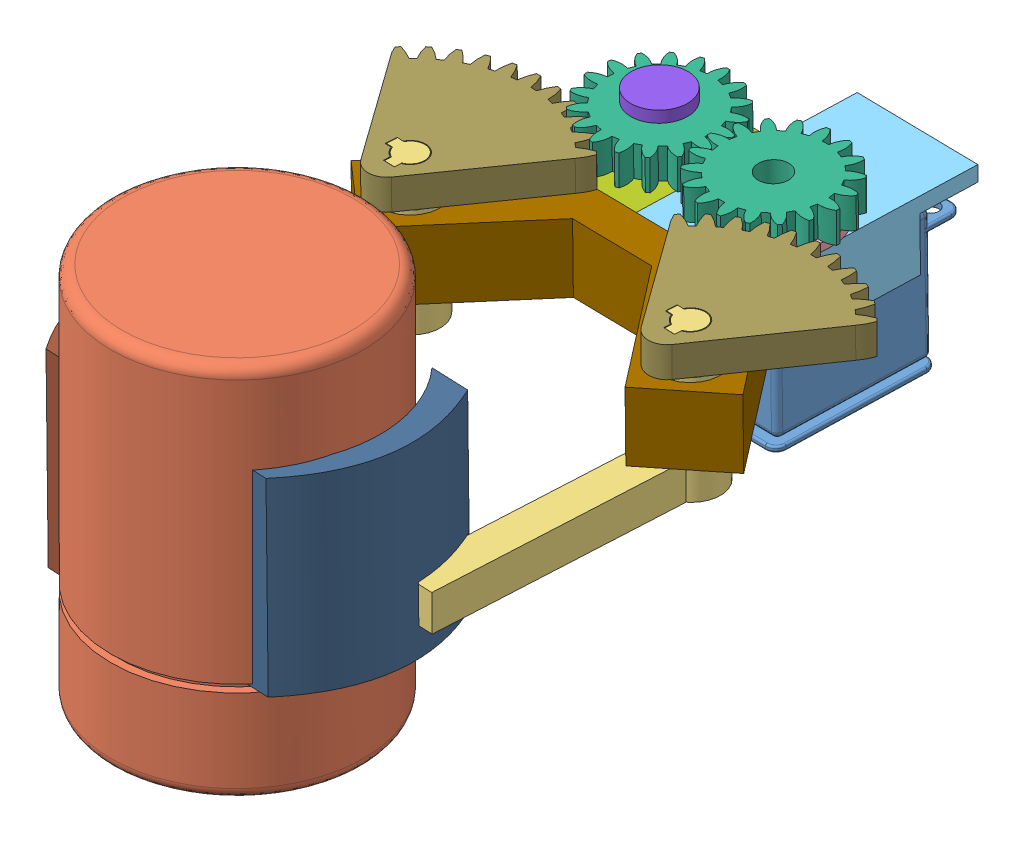
SolidWorks assembly grabber, configuration Default. Lengths in mm.
Overall size (131.25 100 194.6).
15 component instances, 12 part files, 33 mates.
Components (placement in the parent):
- servo-1: servo [Default] at (87.0204 35.4416 14.5462) x (0.029864 0.0013 -0.999553) z (0.999469 0.013011 0.029879) size (56.4 46.15 25.5)
- Can-1: Can [Default] at (74.9527 -0.4819 146.8491) size (67 100 67)
- arm_things-1: arm_things [Default] at (116.9975 33.3778 104.811) x (-0.998549 -0.013024 -0.052251) z (0.052261 -0.000408 -0.998633) size (15 36.5 77.5)
- arm_things-2: arm_things [Default] at (40.0716 32.3764 102.5067) x (-0.998256 -0.013026 -0.057587) z (0.057596 -0.000338 -0.99834) size (15 36.5 77.5)
- smol_white_disc_thing-1: smol_white_disc_thing [Default] at (96.3877 58.9257 25.6615) x (0.99304 0.013061 -0.117048) z (0.11705 0.000622 0.993126) size (30 3.9 30)
- servo_mount-1: servo_mount [Default] at (77.9364 42.1729 14.2653) x (0.999469 0.013011 0.029879) z (-0.02989 0.000699 0.999553) size (35.55 36.2 57.02)
- spur gear_iso-3: spur gear_iso [ISO - Spur gear 1.75M 18T 20PA 8mmFW ---S18A75H50L8.0N] at (96.3369 62.8253 25.665) x (-0.013044 0.999915 0.000911) z (-0.778096 -0.010723 0.628054) size (8 34.62 35)
- spur gear_iso-4: spur gear_iso [ISO - Spur gear 1.75M 18T 20PA 8mmFW ---S18A75H50L8.0N] at (65.1467 62.1199 24.7538) x (-0.012985 0.999915 -0.001088) z (0.609442 0.008776 0.792782) size (8 34.62 35)
- servo_primary_gear_mount_thingy-1: servo_primary_gear_mount_thingy [Default] at (67.6101 55.435 42.47) x (-0.999469 -0.013011 -0.029879) z (0.02989 -0.000699 -0.999553) size (27.5 27.5 35)
- pin_dongley-1: pin_dongley [Default] at (65.0889 64.699 26.8033) x (0.999845 0.012997 0.011858) z (-0.011871 0.000933 0.999929) size (15 17 15)
- big_gear_sticky_thing-1: big_gear_sticky_thing [Default] at (82.3629 42.3781 58.1562) x (0.999469 0.013011 0.029879) z (-0.02989 0.000699 0.999553) size (107.35 18 41.03)
- left_grabby_hand-1: left_grabby_hand [Default] at (76.5862 25.3944 143.4432) x (-0.998549 -0.013024 -0.052251) z (0.052261 -0.000408 -0.998633) size (16.77 50 47.38)
- right_grabby_hand-1: right_grabby_hand [Default] at (76.1966 25.3914 145.3489) x (-0.998256 -0.013026 -0.057587) z (0.057596 -0.000338 -0.99834) size (16.77 50 47.38)
- big_boi_gear_left-1: big_boi_gear_left [Default] at (123.0814 63.1664 59.9132) x (-0.012985 0.999915 -0.001088) z (0.998549 0.013024 0.052251) size (8 45.26 52.07)
- big_boi_gear_left-2: big_boi_gear_left [Default] at (46.3951 62.1681 57.6441) x (-0.012985 0.999915 -0.001088) z (0.998256 0.013026 0.057587) size (8 45.26 52.07)
Mates (geometry in assembly coordinates):
- Coincident8: coincident anti-aligned: line of servo-1 through (96.3482 61.9554 25.6642) axis (0.013044 -0.999915 -0.000911); line of smol_white_disc_thing-1 through (96.3877 58.9257 25.6615) axis (-0.013044 0.999915 0.000911)
- Coincident10: coincident anti-aligned: plane of servo-1 through (96.3482 61.9554 25.6642) normal (-0.013044 0.999915 0.000911); plane of smol_white_disc_thing-1 through (96.3482 61.9554 25.6642) normal (0.013044 -0.999915 -0.000911)
- Coincident11: coincident aligned: line of servo-1 through (84.3492 28.1285 -10.054) axis (-0.999469 -0.013011 -0.029879); line of servo_mount-1 through (82.85 28.109 -10.0989) axis (-0.999469 -0.013011 -0.029879)
- Distance1: distance = 0.1 mm: line of servo_mount-1 through (81.3847 28.1433 38.8992) axis (-0.999469 -0.013011 -0.029879); line of servo-1 through (82.8858 28.0648 38.9241) axis (-0.999469 -0.013011 -0.029879)
- Coincident12: coincident anti-aligned: plane of servo-1 through (82.0231 35.3765 14.3968) normal (-0.999469 -0.013011 -0.029879); plane of servo_mount-1 through (81.9343 42.2249 14.3848) normal (0.999469 0.013011 0.029879)
- Coincident15: coincident anti-aligned: line of smol_white_disc_thing-1 through (96.3629 60.8255 25.6632) axis (-0.013044 0.999915 0.000911); line of spur gear_iso-3 through (96.2325 70.8246 25.6723) axis (0.013044 -0.999915 -0.000911)
- Coincident16: coincident anti-aligned: plane of smol_white_disc_thing-1 through (96.3369 62.8253 25.665) normal (-0.013044 0.999915 0.000911); plane of spur gear_iso-3 through (96.3369 62.8253 25.665) normal (0.013044 -0.999915 -0.000911)
- Coincident17: coincident aligned: line of servo_mount-1 through (78.5536 60.2514 -14.2516) axis (-0.02989 0.000699 0.999553); line of servo_primary_gear_mount_thingy-1 through (77.8954 60.2668 7.7585) axis (-0.02989 0.000699 0.999553)
- Coincident18: coincident aligned: line of servo_mount-1 through (76.8492 60.2913 42.7429) axis (0.012985 -0.999915 0.001088); line of servo_primary_gear_mount_thingy-1 through (76.8492 60.2913 42.7429) axis (0.012985 -0.999915 0.001088)
- Coincident23: coincident anti-aligned: plane of servo_primary_gear_mount_thingy-1 through (65.2116 57.1204 24.7592) normal (-0.012985 0.999915 -0.001088); plane of pin_dongley-1 through (65.1647 57.124 28.7089) normal (0.012985 -0.999915 0.001088)
- Coincident25: coincident aligned: line of servo_primary_gear_mount_thingy-1 through (65.2116 57.1204 24.7592) axis (-0.012985 0.999915 -0.001088); line of pin_dongley-1 through (65.2116 57.1204 24.7592) axis (-0.012985 0.999915 -0.001088)
- Coincident29: coincident anti-aligned: line of spur gear_iso-4 through (65.0428 70.1192 24.7451) axis (0.012985 -0.999915 0.001088); line of pin_dongley-1 through (65.2116 57.1204 24.7592) axis (-0.012985 0.999915 -0.001088)
- Coincident30: coincident anti-aligned: plane of spur gear_iso-4 through (65.1467 62.1199 24.7538) normal (0.012985 -0.999915 0.001088); plane of servo_primary_gear_mount_thingy-1 through (65.1467 62.1199 24.7538) normal (-0.012985 0.999915 -0.001088)
- GearMate1: gear = 18 : 18 mm: line of spur gear_iso-3 through (96.2325 70.8246 25.6723) axis (0.013044 -0.999915 -0.000911); line of spur gear_iso-4 through (65.0428 70.1192 24.7451) axis (0.012985 -0.999915 0.001088)
- Coincident33: coincident aligned: line of servo_mount-1 through (112.3803 60.7538 43.8051) axis (0.012985 -0.999915 0.001088); line of big_gear_sticky_thing-1 through (112.3803 60.7538 43.8051) axis (0.012985 -0.999915 0.001088)
- Coincident34: coincident aligned: line of servo_mount-1 through (112.3803 60.7538 43.8051) axis (-0.999469 -0.013011 -0.029879); line of big_gear_sticky_thing-1 through (112.3803 60.7538 43.8051) axis (-0.999469 -0.013011 -0.029879)
- Coincident43: coincident anti-aligned: line of arm_things-1 through (118.7033 42.8627 69.8485) axis (-0.012985 0.999915 -0.001088); line of big_gear_sticky_thing-1 through (118.4696 60.8612 69.8289) axis (0.012985 -0.999915 0.001088)
- Coincident45: coincident anti-aligned: plane of arm_things-1 through (116.8742 42.877 104.8007) normal (-0.012985 0.999915 -0.001088); plane of big_gear_sticky_thing-1 through (82.3629 42.3781 58.1562) normal (0.012985 -0.999915 0.001088)
- Coincident46: coincident anti-aligned: line of arm_things-1 through (110.3019 42.8294 139.5047) axis (0.012985 -0.999915 0.001088); line of left_grabby_hand-1 through (110.4253 33.3302 139.515) axis (-0.012985 0.999915 -0.001088)
- Coincident47: coincident anti-aligned: line of arm_things-1 through (113.7802 33.3041 75.4068) axis (-0.052261 0.000408 0.998633); line of left_grabby_hand-1 through (110.4253 33.3302 139.515) axis (0.052261 -0.000408 -0.998633)
- Coincident48: coincident aligned: line of arm_things-2 through (42.6741 41.9493 137.7118) axis (0.012985 -0.999915 0.001088); line of right_grabby_hand-1 through (42.6676 42.4492 137.7112) axis (0.012985 -0.999915 0.001088)
- Coincident49: coincident aligned: line of arm_things-2 through (42.7975 32.4501 137.7221) axis (0.057596 -0.000338 -0.99834); line of right_grabby_hand-1 through (42.7975 32.4501 137.7221) axis (0.057596 -0.000338 -0.99834)
- Coincident50: coincident anti-aligned: line of arm_things-2 through (41.9641 41.8637 67.5544) axis (-0.012985 0.999915 -0.001088); line of big_gear_sticky_thing-1 through (41.7304 59.8622 67.5349) axis (0.012985 -0.999915 0.001088)
- Coincident51: coincident anti-aligned: plane of arm_things-2 through (39.9483 41.8756 102.4963) normal (-0.012985 0.999915 -0.001088); plane of big_gear_sticky_thing-1 through (82.3629 42.3781 58.1562) normal (0.012985 -0.999915 0.001088)
- Coincident52: coincident aligned: line of arm_things-1 through (118.3527 69.8605 69.8192) axis (0.012985 -0.999915 0.001088); line of big_boi_gear_left-1 through (118.3527 69.8605 69.8192) axis (0.012985 -0.999915 0.001088)
- Coincident54: coincident anti-aligned: plane of arm_things-1 through (118.4566 61.8611 69.8279) normal (-0.012985 0.999915 -0.001088); plane of big_boi_gear_left-1 through (118.4566 61.8611 69.8279) normal (0.012985 -0.999915 0.001088)
- Parallel1: parallel aligned: line of arm_things-1 through (116.7751 69.8457 75.1151) axis (0.998549 0.013024 0.052251); line of big_boi_gear_left-1 through (116.5727 69.8431 75.1334) axis (0.998549 0.013024 0.052251)
- Coincident57: coincident aligned: line of arm_things-1 through (118.3527 69.8605 69.8192) axis (0.012985 -0.999915 0.001088); line of big_boi_gear_left-1 through (118.3527 69.8605 69.8192) axis (0.012985 -0.999915 0.001088)
- GearMate6: gear = 38 : 18 mm: line of spur gear_iso-3 through (96.2325 70.8246 25.6723) axis (0.013044 -0.999915 -0.000911); line of big_boi_gear_left-1 through (118.3527 69.8605 69.8192) axis (0.012985 -0.999915 0.001088)
- Coincident59: coincident aligned: line of arm_things-2 through (41.6135 68.8615 67.5251) axis (0.012985 -0.999915 0.001088); line of big_boi_gear_left-2 through (41.6135 68.8615 67.5251) axis (0.012985 -0.999915 0.001088)
- Coincident60: coincident anti-aligned: plane of arm_things-2 through (41.7174 60.8621 67.5338) normal (-0.012985 0.999915 -0.001088); plane of big_boi_gear_left-2 through (41.7174 60.8621 67.5338) normal (0.012985 -0.999915 0.001088)
- GearMate9: gear = 38 : 18 mm: line of spur gear_iso-4 through (65.0428 70.1192 24.7451) axis (0.012985 -0.999915 0.001088); line of big_boi_gear_left-2 through (41.6135 68.8615 67.5251) axis (0.012985 -0.999915 0.001088)
- Parallel4: parallel anti-aligned: line of arm_things-2 through (40.0076 68.8463 72.8125) axis (0.998256 0.013026 0.057587); line of big_boi_gear_left-2 through (42.9038 60.8835 73.0112) axis (-0.998256 -0.013026 -0.057587)
